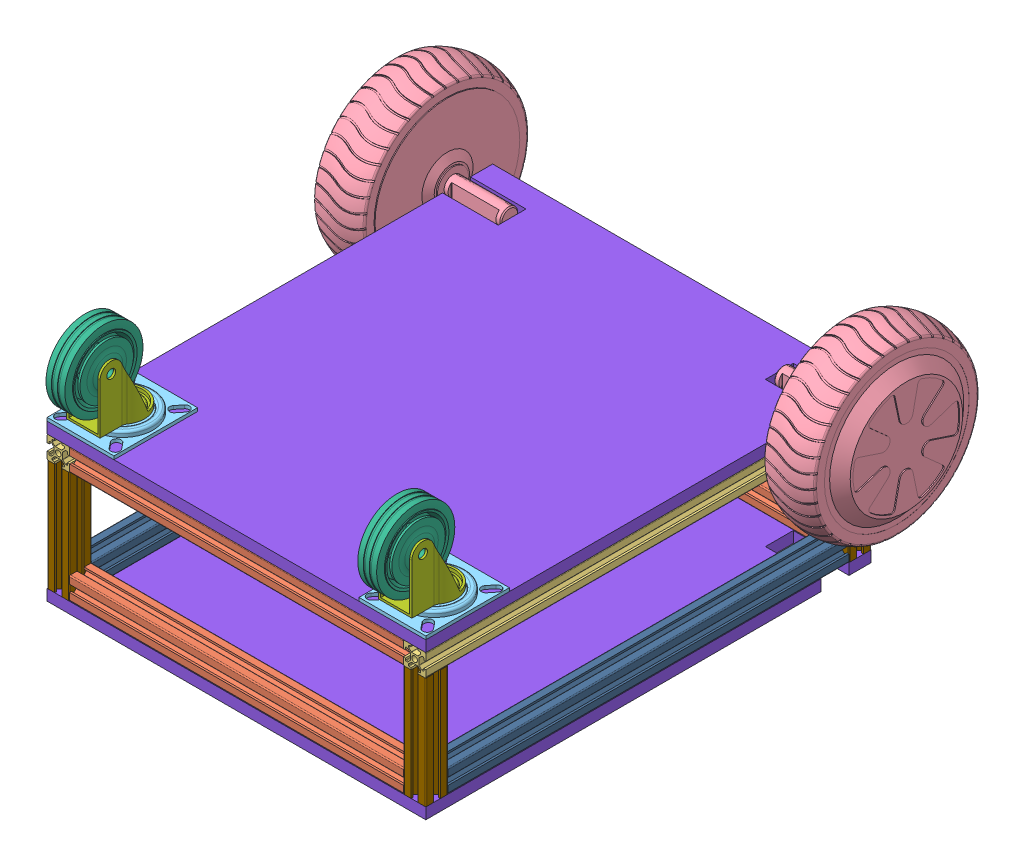
SolidWorks assembly blattoidea, configuration Default. Lengths in mm.
Overall size (467.2 228.08 476.51).
22 component instances, 10 part files, 62 mates.
Components (placement in the parent):
- 2020 alu section_2x300mm-1: 2020 alu section_2x300mm [Default] at (-150 -10 -180) x (0 0 1) z (1 0 0) size (40 20 300)
- 2020 alu section_300mm-1: 2020 alu section_300mm [Default] at (-150 -10 180) x (0 0 1) z (1 0 0) size (20 20 300)
- 2020 alu section_400mm-6: 2020 alu section_400mm [Default] at (-150 -10 -200) x (-1 0 0) z (0 0 1) size (20 20 400)
- 2020 alu section_400mm-5: 2020 alu section_400mm [Default] at (150 -30 200) x (0 1 0) z (0 0 -1) size (20 20 400)
- Motor, BLDC, Hoverboard Wheel, 6.5in-1: Motor, BLDC, Hoverboard Wheel, 6.5in [Default] at (-173.6 -2 -168) x (-1 0 0) z (0 0 1) size (111 171.85 171.85)
- Motor, BLDC, Hoverboard Wheel, 6.5in-2: Motor, BLDC, Hoverboard Wheel, 6.5in [Default] at (173.6 -2 -168) size (111 171.85 171.85)
- Caster_segment1-1: Caster_segment1 [Default] at (-135.5731 53 137.8139) x (0.99524 0 0.097458) z (0.097323 -0.052537 -0.993865) size (67.02 11.45 80.54)
- Caster_segment1-2: Caster_segment1 [Default] at (135.5731 53 187.1861) x (-0.99524 0 -0.097458) z (-0.097323 -0.052537 0.993865) size (67.02 11.45 80.54)
- Caster Wheel-1: Caster Wheel [Default] at (142 53 187.5) x (1 0 0) z (0 0 -1) size (26 70.16 70.16)
- Caster Wheel-2: Caster Wheel [Default] at (-138 53 187.5) size (26 70.16 70.16)
- Caster_segment2-1: Caster_segment2 [Default] at (138 53 187.5) x (-1 0 0) z (0 -0.052537 0.998619) size (40 57.3 55.13)
- Caster_segment2-2: Caster_segment2 [Default] at (-142 53 187.5) x (-1 0 0) z (0 -0.052537 0.998619) size (40 57.3 55.13)
- platform-1: platform [Default] x (-1 0 0) z (0 0 1) size (340 10 400)
- 2020 alu section_100mm-1: 2020 alu section_100mm [Default] at (150 -130 180) x (0 0 1) z (0 1 0) size (20 20 100)
- 2020 alu section_100mm-2: 2020 alu section_100mm [Default] at (-170 -130 180) x (0 0 1) z (0 1 0) size (20 20 100)
- 2020 alu section_100mm-3: 2020 alu section_100mm [Default] at (150 -130 -200) x (0 0 1) z (0 1 0) size (20 20 100)
- 2020 alu section_100mm-4: 2020 alu section_100mm [Default] at (-150 -30 -200) x (0 0 1) z (0 -1 0) size (20 20 100)
- 2020 alu section_300mm-2: 2020 alu section_300mm [Default] at (-150 -110 180) x (0 0 1) z (1 0 0) size (20 20 300)
- 2020 alu section_300mm-3: 2020 alu section_300mm [Default] at (-150 -110 -200) x (0 0 1) z (1 0 0) size (20 20 300)
- 2020 alu section_360mm-4: 2020 alu section_360mm [Default] at (-170 -110 180) x (1 0 0) z (0 0 -1) size (20 20 360)
- 2020 alu section_360mm-5: 2020 alu section_360mm [Default] at (150 -110 180) x (1 0 0) z (0 0 -1) size (20 20 360)
- platform-2: platform [Default] at (0 -130 0) x (-1 0 0) z (0 0 1) size (340 10 400)
Mates (geometry in assembly coordinates):
- Coincident4: coincident anti-aligned: plane of 2020 alu section_2x300mm-1 through (150 -10 -180) normal (1 0 0); plane of 2020 alu section_400mm-5 through (150 -30 -200) normal (-1 0 0)
- Coincident6: coincident anti-aligned: plane of 2020 alu section_300mm-1 through (150 -10 180) normal (1 0 0); plane of 2020 alu section_400mm-5 through (150 -30 -200) normal (-1 0 0)
- Coincident9: coincident aligned: plane of 2020 alu section_300mm-1 through (150 -10 200) normal (0 0 1); plane of 2020 alu section_400mm-5 through (150 -30 200) normal (0 0 1)
- Coincident10: coincident aligned: plane of 2020 alu section_2x300mm-1 through (150 -30 -180) normal (0 -1 0); plane of 2020 alu section_400mm-5 through (150 -30 -200) normal (0 -1 0)
- Coincident11: coincident aligned: plane of 2020 alu section_2x300mm-1 through (150 -10 -200) normal (0 0 -1); plane of 2020 alu section_400mm-5 through (150 -30 -200) normal (0 0 -1)
- Coincident12: coincident aligned: plane of 2020 alu section_300mm-1 through (150 -30 180) normal (0 -1 0); plane of 2020 alu section_400mm-5 through (150 -30 -200) normal (0 -1 0)
- Coincident13: coincident anti-aligned: plane of 2020 alu section_300mm-1 through (-150 -10 180) normal (-1 0 0); plane of 2020 alu section_400mm-6 through (-150 -10 200) normal (1 0 0)
- Coincident14: coincident aligned: plane of 2020 alu section_300mm-1 through (150 -10 200) normal (0 0 1); plane of 2020 alu section_400mm-6 through (-150 -10 200) normal (0 0 1)
- Coincident15: coincident aligned: plane of 2020 alu section_300mm-1 through (150 -30 180) normal (0 -1 0); plane of 2020 alu section_400mm-6 through (-150 -30 200) normal (0 -1 0)
- Coincident33: coincident anti-aligned: plane of 2020 alu section_400mm-5 through (170 -30 -200) normal (1 0 0); plane of Motor, BLDC, Hoverboard Wheel, 6.5in-2 through (170 -2 -157) normal (-1 0 0)
- Tangent2: tangent aligned: plane of 2020 alu section_2x300mm-1 through (150 -10 -160) normal (0 0 1); cylinder of Motor, BLDC, Hoverboard Wheel, 6.5in-2 through (148.1 -2 -168) axis (-1 0 0) radius 8
- Coincident36: coincident aligned: plane of 2020 alu section_300mm-1 through (150 -10 200) normal (0 0 1); plane of Caster_segment1-1 through (-140 0 200) normal (0 0 1)
- Coincident37: coincident aligned: plane of 2020 alu section_400mm-6 through (-170 -10 200) normal (-1 0 0); plane of Caster_segment1-1 through (-170 0 162.5) normal (-1 0 0)
- Distance4: distance = 0 mm anti-aligned: plane of Caster_segment1-1 through (-140 0 162.5) normal (0 -1 0); plane of platform-1 through (0 0 0) normal (0 1 0)
- Distance5: distance = 0 mm anti-aligned: plane of Caster_segment1-2 through (140 0 162.5) normal (0 -1 0); plane of platform-1 through (0 0 0) normal (0 1 0)
- Tangent6: tangent anti-aligned: plane of 2020 alu section_400mm-6 through (-150 -10 200) normal (0 1 0); cylinder of Motor, BLDC, Hoverboard Wheel, 6.5in-1 through (-148.1 -2 -168) axis (1 0 0) radius 8
- Coincident49: coincident anti-aligned: plane of 2020 alu section_400mm-6 through (-170 -10 200) normal (-1 0 0); plane of Motor, BLDC, Hoverboard Wheel, 6.5in-1 through (-170 -2 -157) normal (1 0 0)
- Tangent7: tangent aligned: plane of 2020 alu section_2x300mm-1 through (150 -10 -160) normal (0 0 1); cylinder of Motor, BLDC, Hoverboard Wheel, 6.5in-1 through (-148.1 -2 -168) axis (1 0 0) radius 8
- Tangent8: tangent anti-aligned: plane of 2020 alu section_400mm-5 through (150 -10 -200) normal (0 1 0); cylinder of Motor, BLDC, Hoverboard Wheel, 6.5in-2 through (148.1 -2 -168) axis (-1 0 0) radius 8
- Concentric3: concentric aligned: circle of Caster_segment1-2; circle of Caster_segment2-1
- Coincident50: coincident anti-aligned: plane of Caster_segment1-2 through (140 8 162.5) normal (0 1 0); plane of Caster_segment2-1 through (155 8 187.5) normal (0 -1 0)
- Concentric4: concentric aligned: cylinder of Caster Wheel-1 through (149 53 187.5) axis (1 0 0) radius 4; cylinder of Caster_segment2-1 through (125 53 187.5) axis (1 0 0) radius 4
- Coincident52: coincident anti-aligned: plane of Caster Wheel-1 through (127 53 187.5) normal (-1 0 0); plane of Caster_segment2-1 through (127 53 187.5) normal (1 0 0)
- Concentric5: concentric aligned: circle of Caster_segment1-1; circle of Caster_segment2-2
- Coincident53: coincident anti-aligned: plane of Caster_segment1-1 through (-140 8 162.5) normal (0 1 0); plane of Caster_segment2-2 through (-125 8 187.5) normal (0 -1 0)
- Concentric6: concentric anti-aligned: cylinder of Caster Wheel-2 through (-149 53 187.5) axis (-1 0 0) radius 4; cylinder of Caster_segment2-2 through (-155 53 187.5) axis (1 0 0) radius 4
- Coincident56: coincident aligned: plane of 2020 alu section_400mm-5 through (170 -30 -200) normal (1 0 0); plane of platform-1 through (170 -10 200) normal (1 0 0)
- Coincident57: coincident aligned: plane of 2020 alu section_2x300mm-1 through (150 -10 -200) normal (0 0 -1); plane of platform-1 through (170 -10 -200) normal (0 0 -1)
- Coincident59: coincident aligned: plane of platform-1 through (170 -10 200) normal (1 0 0); plane of 2020 alu section_100mm-3 through (170 -30 -200) normal (1 0 0)
- Coincident60: coincident aligned: plane of platform-1 through (170 -10 -200) normal (0 0 -1); plane of 2020 alu section_100mm-3 through (150 -30 -200) normal (0 0 -1)
- Coincident62: coincident aligned: plane of platform-1 through (170 -10 200) normal (1 0 0); plane of 2020 alu section_100mm-1 through (170 -30 180) normal (1 0 0)
- Coincident63: coincident aligned: plane of platform-1 through (170 -10 200) normal (0 0 1); plane of 2020 alu section_100mm-1 through (150 -30 200) normal (0 0 1)
- Coincident65: coincident aligned: plane of platform-1 through (170 -10 200) normal (0 0 1); plane of 2020 alu section_100mm-2 through (-170 -30 200) normal (0 0 1)
- Coincident66: coincident aligned: plane of platform-1 through (-170 -10 200) normal (-1 0 0); plane of 2020 alu section_100mm-2 through (-170 -30 180) normal (-1 0 0)
- Coincident68: coincident aligned: plane of platform-1 through (-170 -10 200) normal (-1 0 0); plane of 2020 alu section_100mm-4 through (-170 -130 -200) normal (-1 0 0)
- Coincident69: coincident aligned: plane of platform-1 through (170 -10 -200) normal (0 0 -1); plane of 2020 alu section_100mm-4 through (-150 -130 -200) normal (0 0 -1)
- Coincident70: coincident anti-aligned: plane of 2020 alu section_100mm-3 through (150 -30 -200) normal (-1 0 0); plane of 2020 alu section_300mm-3 through (150 -110 -200) normal (1 0 0)
- Coincident71: coincident aligned: plane of 2020 alu section_100mm-3 through (150 -30 -180) normal (0 0 1); plane of 2020 alu section_300mm-3 through (150 -110 -180) normal (0 0 1)
- Coincident72: coincident aligned: plane of 2020 alu section_100mm-3 through (150 -130 -200) normal (0 -1 0); plane of 2020 alu section_300mm-3 through (150 -130 -200) normal (0 -1 0)
- Coincident73: coincident anti-aligned: plane of 2020 alu section_100mm-2 through (-150 -30 180) normal (1 0 0); plane of 2020 alu section_300mm-2 through (-150 -110 180) normal (-1 0 0)
- Coincident74: coincident aligned: plane of 2020 alu section_100mm-2 through (-170 -130 180) normal (0 -1 0); plane of 2020 alu section_300mm-2 through (150 -130 180) normal (0 -1 0)
- Coincident75: coincident aligned: plane of 2020 alu section_100mm-2 through (-170 -30 200) normal (0 0 1); plane of 2020 alu section_300mm-2 through (150 -110 200) normal (0 0 1)
- Coincident79: coincident anti-aligned: plane of 2020 alu section_100mm-4 through (-150 -130 -180) normal (0 0 1); plane of 2020 alu section_360mm-4 through (-170 -110 -180) normal (0 0 -1)
- Coincident80: coincident aligned: plane of 2020 alu section_100mm-4 through (-150 -130 -200) normal (0 -1 0); plane of 2020 alu section_360mm-4 through (-170 -130 -180) normal (0 -1 0)
- Coincident81: coincident aligned: plane of 2020 alu section_100mm-4 through (-150 -130 -200) normal (1 0 0); plane of 2020 alu section_360mm-4 through (-150 -110 -180) normal (1 0 0)
- Coincident82: coincident anti-aligned: plane of 2020 alu section_100mm-1 through (150 -30 180) normal (0 0 -1); plane of 2020 alu section_360mm-5 through (150 -110 180) normal (0 0 1)
- Coincident83: coincident aligned: plane of 2020 alu section_100mm-1 through (150 -130 180) normal (0 -1 0); plane of 2020 alu section_360mm-5 through (150 -130 -180) normal (0 -1 0)
- Coincident84: coincident aligned: plane of 2020 alu section_100mm-1 through (150 -30 180) normal (-1 0 0); plane of 2020 alu section_360mm-5 through (150 -110 -180) normal (-1 0 0)
- Coincident86: coincident anti-aligned: plane of 2020 alu section_300mm-2 through (150 -130 180) normal (0 -1 0); plane of platform-2 through (0 -130 0) normal (0 1 0)
- Coincident87: coincident aligned: plane of 2020 alu section_300mm-2 through (150 -110 200) normal (0 0 1); plane of platform-2 through (170 -140 200) normal (0 0 1)
- Coincident88: coincident aligned: plane of 2020 alu section_360mm-4 through (-170 -110 -180) normal (-1 0 0); plane of platform-2 through (-170 -140 200) normal (-1 0 0)
- Coincident89: coincident anti-aligned: plane of 2020 alu section_2x300mm-1 through (150 -10 -180) normal (0 1 0); plane of platform-1 through (0 -10 0) normal (0 -1 0)
- Coincident90: coincident anti-aligned: plane of 2020 alu section_400mm-6 through (-150 -30 200) normal (0 -1 0); plane of 2020 alu section_100mm-4 through (-150 -30 -200) normal (0 1 0)
- Coincident91: coincident anti-aligned: plane of 2020 alu section_400mm-6 through (-150 -30 200) normal (0 -1 0); plane of 2020 alu section_100mm-2 through (-170 -30 180) normal (0 1 0)
- Coincident92: coincident anti-aligned: plane of 2020 alu section_400mm-5 through (150 -30 -200) normal (0 -1 0); plane of 2020 alu section_100mm-1 through (150 -30 180) normal (0 1 0)
- Coincident93: coincident aligned: plane of Caster_segment1-2 through (140 0 200) normal (0 0 1); plane of platform-1 through (170 -10 200) normal (0 0 1)
- Coincident94: coincident aligned: plane of Caster_segment1-2 through (170 0 162.5) normal (1 0 0); plane of platform-1 through (170 -10 200) normal (1 0 0)
- Coincident95: coincident anti-aligned: plane of 2020 alu section_400mm-5 through (150 -30 -200) normal (0 -1 0); plane of 2020 alu section_100mm-3 through (150 -30 -200) normal (0 1 0)
- Parallel2: parallel aligned: plane of platform-2 through (170 -140 200) normal (0 0 1)
- Parallel3: parallel anti-aligned: plane of platform-2 through (0 -140 0) normal (0 -1 0)
- Coincident101: coincident anti-aligned: plane of Caster Wheel-2 through (-127 53 187.5) normal (1 0 0); plane of Caster_segment2-2 through (-127 53 187.5) normal (-1 0 0)
- Distance8: distance = 200 mm: line of assembly; point of assembly; line of platform-1 through (170 0 200) axis (-1 0 0)
